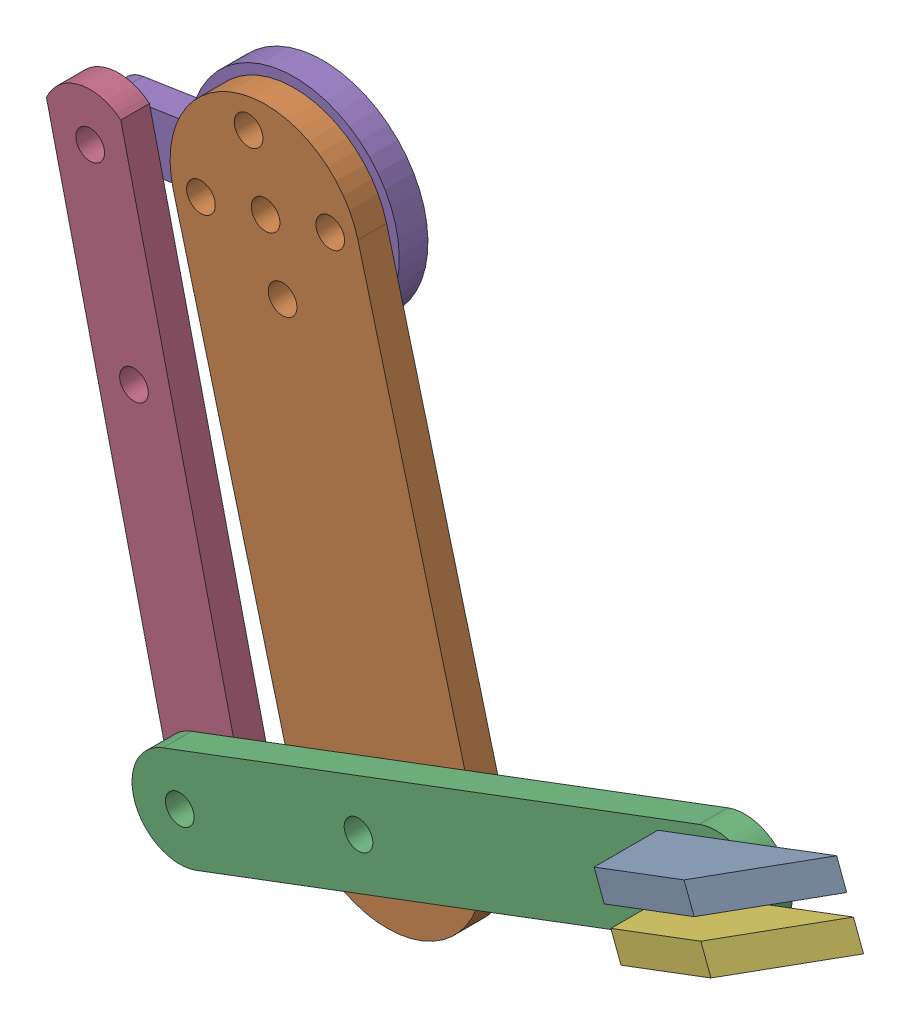
SolidWorks assembly ARM NEW, configuration Default. Lengths in mm.
Overall size (89.02 74.39 15.68).
6 component instances, 5 part files, 10 mates.
Components (placement in the parent):
- claw-1: claw [Default] at (49.4393 -15.5942 20.7986) x (-0.935902 -0.352261 0) z (0 0 -1) size (20 3 9.68)
- d1-1: d1 [Default] at (13.9733 22.039 17.7986) x (-0.25464 0.967036 0) z (0.967036 0.25464 0) size (70 3 20)
- d2-1: d2 [Default] at (56.2323 -19.4483 20.7986) x (0.935902 0.352261 0) z (0.352261 -0.935902 0) size (70 3 10)
- hand2-1: hand2 [Default] at (-4.8888 -39.7415 17.7986) x (0.229248 -0.973368 0) z (-0.973368 -0.229248 0) size (64 3 8)
- hand3-1: hand3 [Default] at (4.303 19.4926 14.7986) x (-0.152567 0.988293 0) z (0.988293 0.152567 0) size (22 3 32.58)
- claw-2: claw [Default] at (51.2006 -20.2737 20.7986) x (-0.935902 -0.352261 0) z (0 0 -1) size (20 3 9.68)
Mates (geometry in assembly coordinates):
- Coincident2: coincident anti-aligned: plane of d2-1 through (54.8233 -15.7047 23.7986) normal (-0.935902 -0.352261 0); plane of claw-2 through (54.8233 -15.7047 20.7986) normal (0.935902 0.352261 0)
- Coincident3: coincident anti-aligned: plane of d2-1 through (55.8801 -18.5124 23.7986) normal (-0.352261 0.935902 0); plane of claw-2 through (51.2006 -20.2737 20.7986) normal (0.352261 -0.935902 0)
- Coincident4: coincident anti-aligned: line of d2-1 through (55.8801 -18.5124 20.7986) axis (-0.352261 0.935902 0); line of claw-2 through (54.8233 -15.7047 20.7986) axis (0.352261 -0.935902 0)
- Coincident5: coincident anti-aligned: plane of claw-1 through (53.062 -11.0251 20.7986) normal (0.935902 0.352261 0); plane of d2-1 through (54.1188 -13.8329 23.7986) normal (-0.935902 -0.352261 0)
- Coincident6: coincident anti-aligned: plane of claw-1 through (49.4393 -15.5942 20.7986) normal (0.352261 -0.935902 0); plane of d2-1 through (54.1188 -13.8329 23.7986) normal (-0.352261 0.935902 0)
- Coincident7: coincident anti-aligned: line of claw-1 through (53.062 -11.0251 20.7986) axis (0.352261 -0.935902 0); line of d2-1 through (54.1188 -13.8329 20.7986) axis (-0.352261 0.935902 0)
- Coincident8: coincident aligned: circle of d1-1; circle of d2-1
- Coincident9: coincident aligned: circle of d2-1; circle of hand2-1
- Coincident10: coincident aligned: circle of hand2-1; circle of hand3-1
- Concentric2: concentric aligned: circle of d1-1; circle of hand3-1
